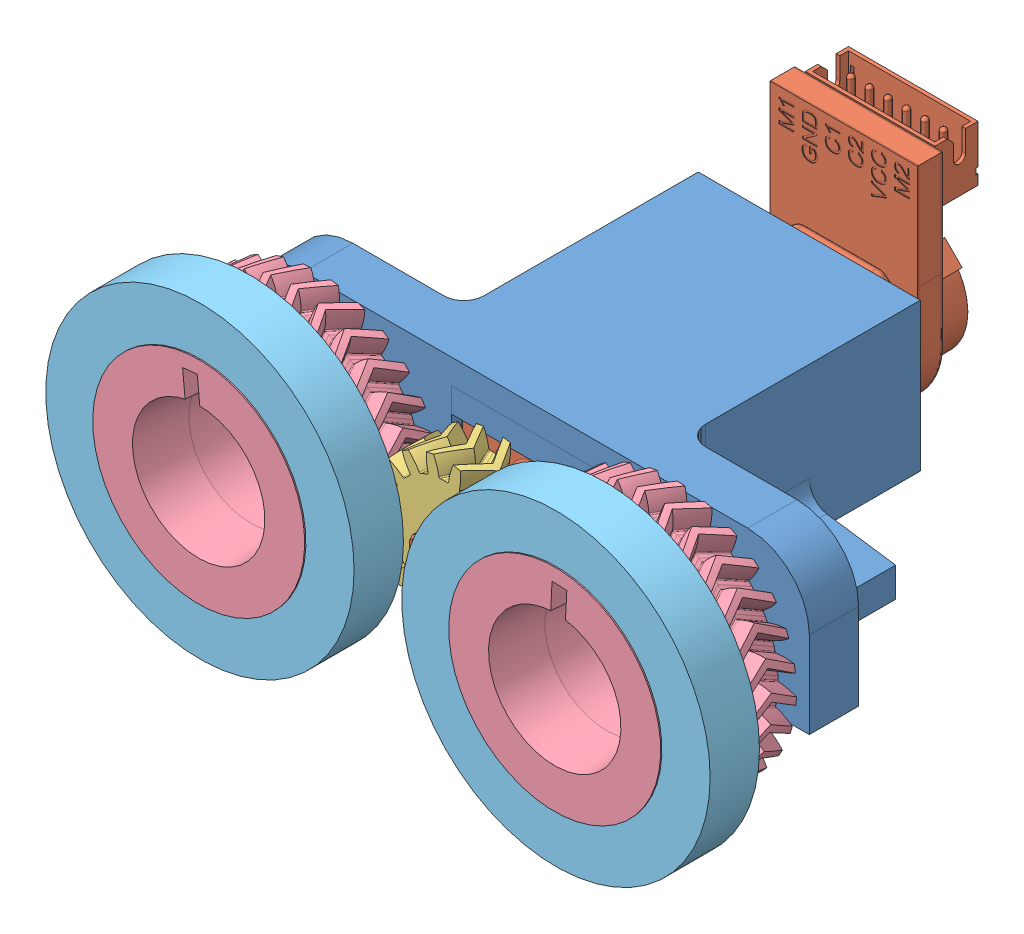
SolidWorks assembly Single Motor Unit, configuration Default. Lengths in mm.
Overall size (54.01 26.01 43.54).
7 component instances, 5 part files, 11 mates.
Components (placement in the parent):
- Motor Mount-1: Motor Mount [Default] at (16.3484 20.4702 45.5682) size (46 12 23)
- N20 Mini Micro Metall Gear Motor-1: N20 Mini Micro Metall Gear Motor [Default] at (16.3484 25.4702 34.9682) x (0 0 1) z (0 1 0) size (39.8 12.15 18.58)
- Motor Gear-1: Motor Gear [Default] at (16.2947 25.47 52.04) x (0 -1 0) z (0.01309 0 -0.999914) size (12.06 12.03 5.01)
- Wheel Gear-2: Wheel Gear [Default] at (30.8484 25.4702 48.105) x (0.998695 -0.051069 0) z (0 0 1) size (20.04 20.04 10.6)
- Wheel Gear-3: Wheel Gear [Default] at (1.8484 25.4702 47.9672) x (0.995465 0.095129 0) z (0 0 1) size (20.04 20.04 10.6)
- Tire 4mm-1: Tire 4mm [Default] at (1.8484 25.4702 50.4672) x (0.999999 -0.001124 0) z (0 0 1) size (25 25 4)
- Tire 4mm-2: Tire 4mm [Default] at (30.8484 25.4702 50.605) size (25 25 4)
Mates (geometry in assembly coordinates):
- Coincident1: coincident anti-aligned: plane of Motor Mount-1 through (16.3484 20.4702 44.7682) normal (0 0 -1); plane of N20 Mini Micro Metall Gear Motor-1 through (22.3484 20.4702 44.7682) normal (0 0 1)
- Coincident2: coincident anti-aligned: plane of Motor Mount-1 through (10.3484 30.4702 35.3682) normal (0 -1 0); plane of N20 Mini Micro Metall Gear Motor-1 through (22.3484 30.4702 43.9682) normal (0 1 0)
- Width1: width anti-aligned: plane of Motor Mount-1 through (22.3484 20.4702 35.3682) normal (-1 0 0); plane of N20 Mini Micro Metall Gear Motor-1 through (10.3484 20.4702 35.3682) normal (1 0 0); plane of Motor Mount-1 through (22.3484 20.4702 34.9682) normal (1 0 0); plane of N20 Mini Micro Metall Gear Motor-1 through (10.3484 30.4702 34.9682) normal (-1 0 0)
- Coincident6: coincident anti-aligned: plane of N20 Mini Micro Metall Gear Motor-1 through (15.3484 23.4702 45.9682) normal (-1 0 0); plane of Motor Gear-1 through (15.3484 26.72 48.0273) normal (1 0 0)
- Symmetric3: symmetric aligned: plane of Motor Gear-1 through (17.8962 25.07 48.0606) normal (0.000171 0.999914 -0.013088); plane of Motor Gear-1 through (19.696 25.87 48.0842) normal (0.000171 -0.999914 -0.013088)
- Concentric11: concentric aligned: cylinder of Motor Mount-1 through (30.8484 25.4702 22.5682) axis (0 0 1) radius 1.6; cylinder of Wheel Gear-2 through (30.8484 25.4702 48.0999) axis (0 0 1) radius 4
- Concentric12: concentric aligned: cylinder of Motor Mount-1 through (1.8484 25.4702 22.5682) axis (0 0 1) radius 1.6; cylinder of Wheel Gear-3 through (1.8484 25.4702 47.9621) axis (0 0 1) radius 4
- Concentric13: concentric: cylinder of Motor Mount-1 through (1.8484 25.4702 22.5682) axis (0 0 1) radius 1.6; cylinder of Tire 4mm-1 through (1.8484 25.4702 52.6164) axis (0 0 1) radius 12.5
- Distance4: distance = 0.1 mm aligned: plane of Tire 4mm-1 through (1.8484 25.4702 57.4672) normal (0 0 1); plane of Wheel Gear-3 through (1.8484 25.4702 57.5672) normal (0 0 1)
- Distance5: distance = 0.1 mm: plane of Tire 4mm-2 through (30.8484 25.4702 57.605) normal (0 0 1); plane of Wheel Gear-2 through (30.8484 25.4702 57.705) normal (0 0 1)
- Concentric14: concentric aligned: cylinder of Motor Mount-1 through (30.8484 25.4702 22.5682) axis (0 0 1) radius 1.6; cylinder of Tire 4mm-2 through (30.8484 25.4702 53.605) axis (0 0 1) radius 12.5
